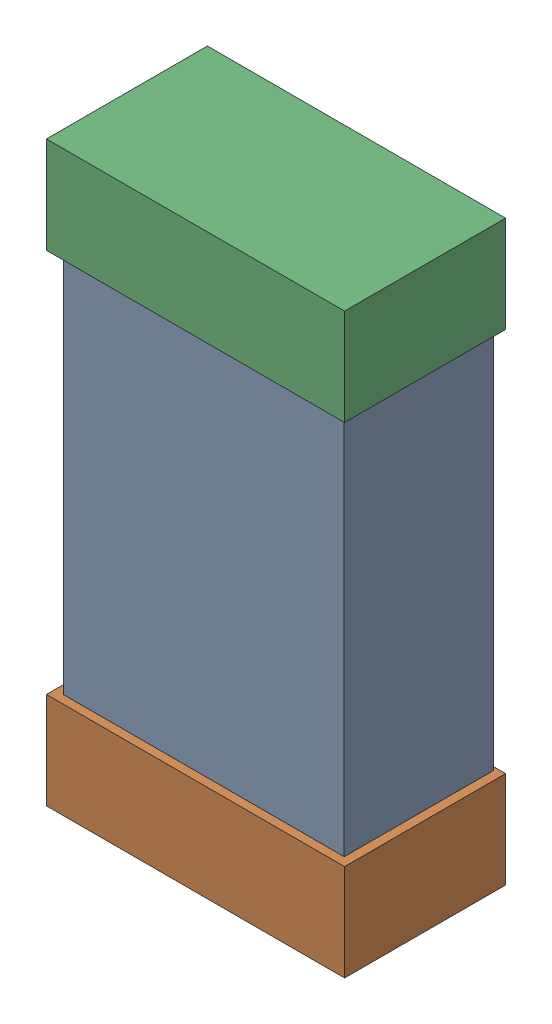
SolidWorks assembly PWR4, configuration Default. Lengths in mm.
Overall size (0.85 1.65 0.46).
6 component instances, 2 part files, 0 mates.
Components (placement in the parent):
- 432124816_42-1: 432124816_42 [Default] at (35.9501 60.7688 -0.8615) size (0.8 1.5 0.42)
  - Extruded (1)-1: Extruded (1) [Default] at origin size (0.8 1.5 0.42)
- 432138512_84-1: 432138512_84 [Default] at (35.9501 60.083 -0.8715) size (0.85 0.28 0.46)
  - Extruded-1: Extruded [Default] at origin size (0.85 0.28 0.46)
- 432138512_85-1: 432138512_85 [Default] at (35.9501 61.4545 -0.8715) size (0.85 0.28 0.46)
  - Extruded-1: Extruded [Default] at origin size (0.85 0.28 0.46)
